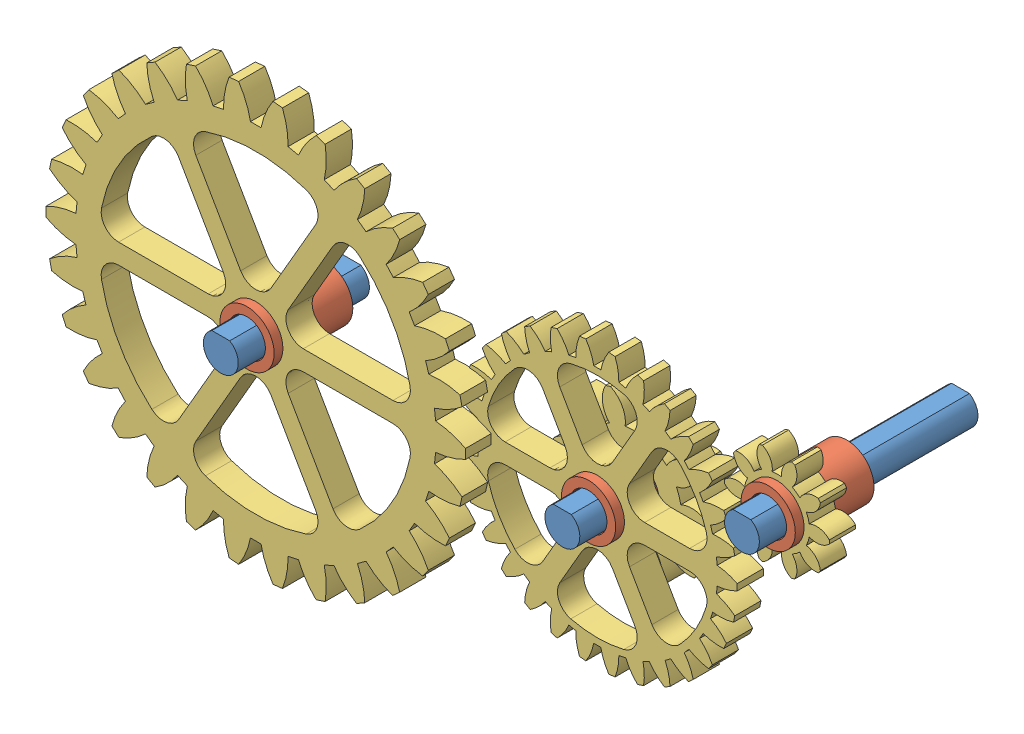
SolidWorks assembly Assem1, configuration Default. Lengths in mm.
Overall size (87.21 47.84 27.4).
17 component instances, 3 part files, 1 mates.
Components (placement in the parent):
- input_shaft-1: input_shaft [Default] at (-0.4485 1.5178 -0.89) size (12 11.53 25)
  - axle-1: axle [25mm] at (9.6586 13.3599 6.3997) size (4 3.72 25)
  - spacer-2: spacer [4.2mm ID 5L] at (9.6586 13.3599 19.3997) size (6.2 6.2 5)
  - root_gear-1: root_gear [10T 1.0Mod] at (9.6586 13.3599 24.3997) size (12 11.53 3)
  - spacer-5: spacer [4.2mm ID 1L] at (9.6586 13.3599 27.3997) x (0.979964 -0.199174 0) z (0 0 1) size (6.2 6.2 1)
- assem_2-1: assem_2 [Default] at (-18.837 -3.4321 11.7144) size (32 31.89 15)
  - axle-1: axle [15mm] at (6.9674 8.0145 3.2605) size (4 3.72 15)
  - root_gear-1: root_gear [30T 1.0Mod] at (6.9674 8.0145 11.2605) size (32 31.89 3)
  - root_gear-2: root_gear [10T 1.5Mod] at (6.9674 8.0145 7.2605) size (18 17.3 3)
  - spacer-1: spacer [4.2mm ID 1L] at (6.9674 8.0145 6.2605) size (6.2 6.2 1)
  - spacer-2: spacer [4.2mm ID 1L] at (6.9674 8.0145 14.2605) x (0.300873 0.953664 0) z (0 0 1) size (6.2 6.2 1)
  - spacer-3: spacer [4.2mm ID 1L] at (6.9674 8.0145 10.2605) x (0.999497 0.031723 0) z (0 0 1) size (6.2 6.2 1)
- Assem3-1: Assem3 [Default] at (-58.97 -6.3038 4.4812) size (48 47.84 15)
  - spacer-1: spacer [4.2mm ID 1L] at (10.9723 11.4982 24.4305) x (0.97362 0.228174 0) z (0 0 1) size (6.2 6.2 1)
  - spacer-2: spacer [4.2mm ID 5L] at (10.9723 11.4982 16.4305) x (0.545669 0.838001 0) z (0 0 1) size (6.2 6.2 5)
  - root_gear-1: root_gear [30T 1.5Mod] at (10.9723 11.4982 21.4305) size (48 47.84 3)
  - axle-2: axle [15mm] at (10.9723 11.4982 13.4305) size (4 3.72 15)
Mates (geometry in assembly coordinates):
- GearMate1: gear = 12 : 27.5 mm: cylinder of assem_2-1/root_gear-1 through (-11.8696 4.5823 25.9749) axis (0 0 -1) radius 13.75; cylinder of input_shaft-1/root_gear-1 through (9.2101 14.8777 26.5097) axis (0 0 -1) radius 6
